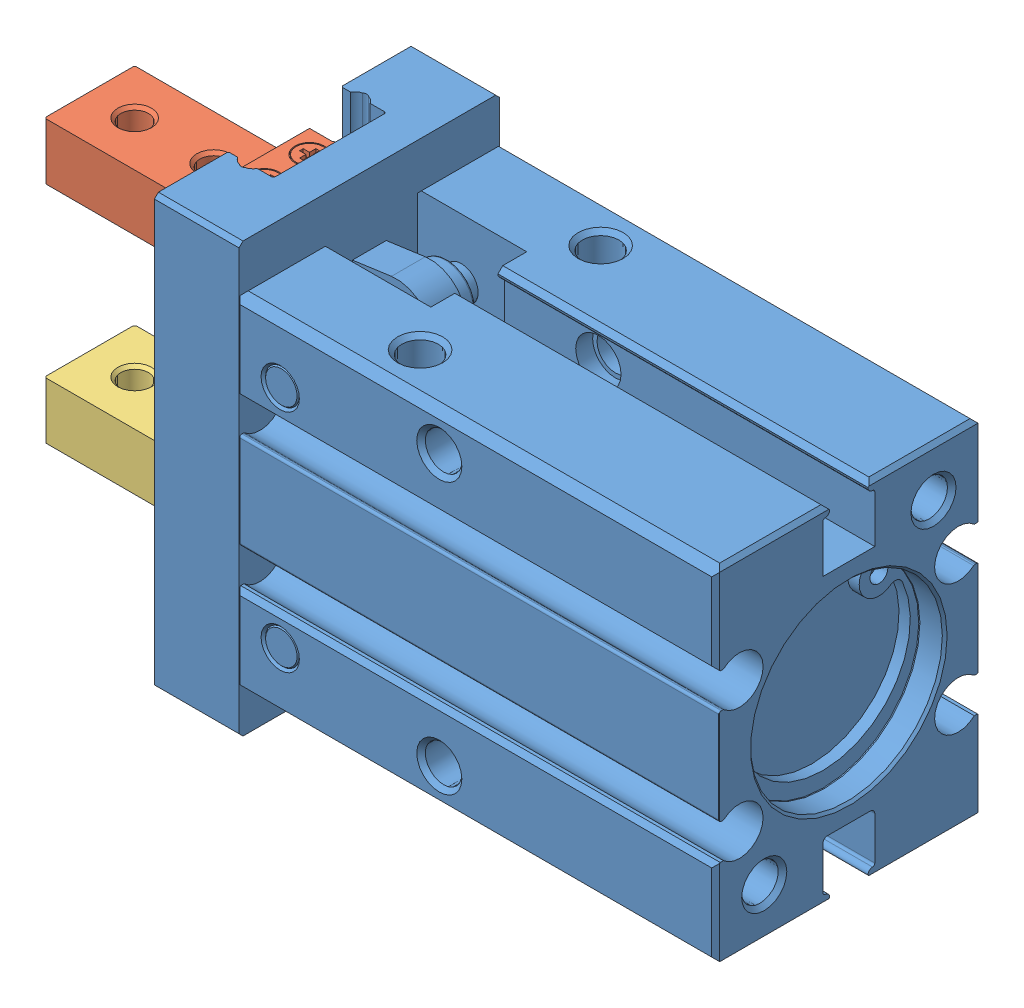
SolidWorks assembly Assem1, configuration Default. Lengths in mm.
Overall size (67.3 38 23.6).
3 component instances, 3 part files, 6 mates.
Components (placement in the parent):
- body-1: body [默认] at (49.8346 27.6237 34.083) size (50 38 23.6)
- ljaw-1: ljaw [默认] at (49.8346 27.6137 34.083) size (21.3 15.4 11.12)
- rjaw-1: rjaw [默认] at (49.8346 27.6337 34.083) size (21.3 15.6 11.12)
Mates (geometry in assembly coordinates):
- Concentric1: concentric aligned: cylinder of body-1 through (1.5346 46.6237 39.243) axis (0 1 0) radius 0.4; cylinder of ljaw-1 through (1.5346 -17.3863 39.243) axis (0 1 0) radius 0.4
- Parallel1: parallel aligned: plane of body-1 through (-0.1654 27.6237 34.083) normal (-1 0 0); plane of ljaw-1 through (-1.9654 27.6237 38.083) normal (-1 0 0)
- Concentric2: concentric aligned: cylinder of body-1 through (1.5346 46.6237 39.243) axis (0 1 0) radius 0.4; cylinder of rjaw-1 through (1.5346 -17.3663 39.243) axis (0 1 0) radius 0.4
- Parallel2: parallel aligned: plane of body-1 through (-0.1654 27.6237 34.083) normal (-1 0 0); plane of rjaw-1 through (-1.9654 27.6237 30.083) normal (-1 0 0)
- LimitDistance1: limit distance = 0 mm: point of ljaw-1; moEndPointRef_w of body-1
- LimitDistance2: limit distance = 0 mm: plane of rjaw-1 through (49.8346 27.6237 34.083) normal (0 1 0); unknown of body-1
